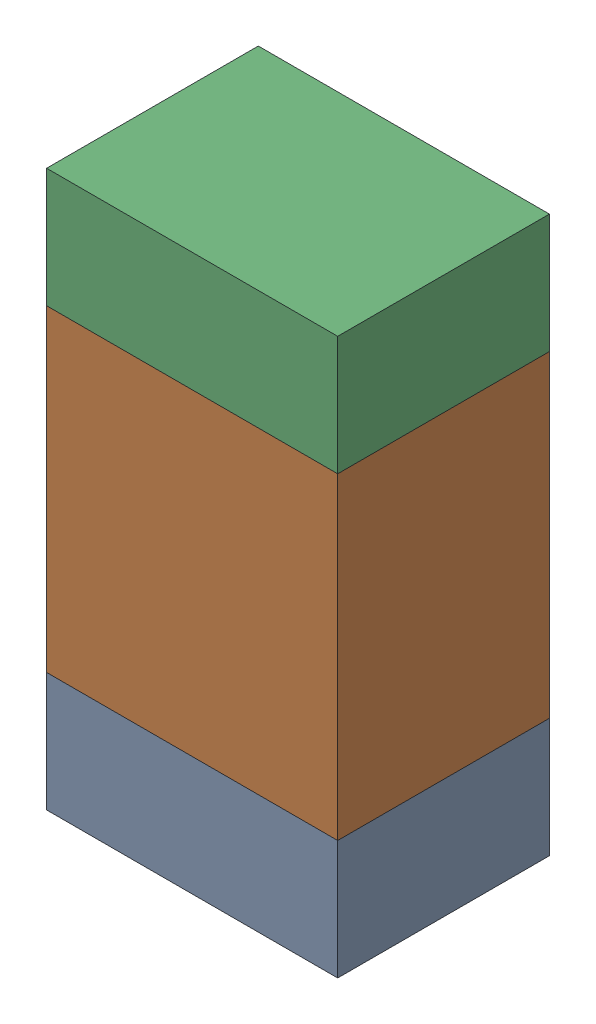
SolidWorks assembly R108_2PCB, configuration Default. Lengths in mm.
Overall size (0.55 1.05 0.4).
6 component instances, 2 part files, 0 mates.
Components (placement in the parent):
- 846483288-1: 846483288 [Default] at (115.0999 96.6876 0) size (0.55 0.22 0.4)
  - Extruded_12-1: Extruded_12 [Default] at origin size (0.55 0.22 0.4)
- 846483424-1: 846483424 [Default] at (115.0999 97.1001 0) size (0.55 0.6 0.4)
  - Extruded_13-1: Extruded_13 [Default] at origin size (0.55 0.6 0.4)
- 846483288-2: 846483288 [Default] at (115.0999 97.5126 0) size (0.55 0.22 0.4)
  - Extruded_12-1: Extruded_12 [Default] at origin size (0.55 0.22 0.4)
